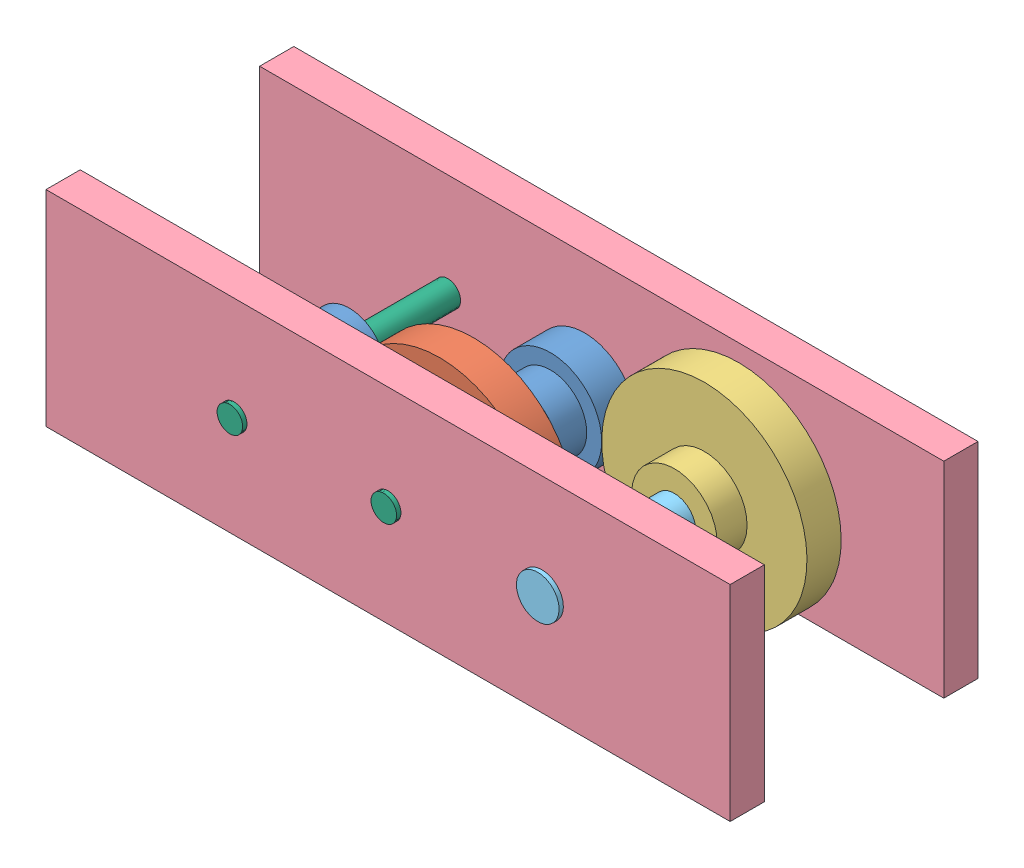
SolidWorks assembly Assem2, configuration Default. Lengths in mm.
Overall size (508 199.15 190.5).
9 component instances, 6 part files, 18 mates.
Components (placement in the parent):
- gear1-1: gear1 [Default] at (-46.2625 76.2 262.9741) x (-1 0 0) z (0 0 -1) size (76.2 76.2 47.5)
- gear2-1: gear2 [Default] at (68.0375 76.2 237.5741) x (0.923728 -0.383049 0) z (0 0 1) size (152.4 152.4 47.62)
- gear1-2: gear1 [Default] at (68.0375 76.2 155.1511) x (0.923728 -0.383049 0) z (0 0 1) size (76.2 76.2 47.5)
- gear3-1: gear3 [Default] at (182.3375 76.2 155.1511) x (0.923728 -0.383049 0) z (0 0 1) size (152.4 152.4 47.62)
- side-1: side [Default] at (68.0375 76.2 301.0741) x (1 0 0) z (0 0 -1) size (508 152.4 25.4)
- rod2-1: rod2 [Default] at (182.3375 76.2 304.2491) x (0.923728 -0.383049 0) z (0.383049 0.923728 0) size (31.75 190.5 31.75)
- side-2: side [Default] at (68.0375 76.2 117.0511) size (508 152.4 25.4)
- rod1-1: rod1 [Default] at (68.0375 76.2 113.7491) x (0 0 1) z (-0.923728 0.383049 0) size (190.5 19.05 19.05)
- rod1-2: rod1 [Default] at (-46.2625 76.2 113.7491) x (0 0 1) z (-0.923728 0.383049 0) size (190.5 19.05 19.05)
Mates (geometry in assembly coordinates):
- Distance1: distance = 12.7 mm anti-aligned: plane of gear2-1 through (68.0375 76.2 262.9741) normal (0 0 1); plane of side-1 through (68.0375 76.2 275.6741) normal (0 0 -1)
- Concentric3: concentric aligned: cylinder of gear2-1 through (36.132 5.8682 215.3491) axis (0 0 1) radius 31.75; cylinder of side-1 through (36.132 5.8682 275.6741) axis (0 0 1) radius 9.525
- Concentric4: concentric aligned: cylinder of gear1-1 through (-69.4501 -37.9143 237.5741) axis (0 0 1) radius 38.1; cylinder of side-1 through (-69.4501 -37.9143 275.6741) axis (0 0 1) radius 9.525
- Coincident2: coincident aligned: plane of gear1-1 through (-69.4501 -37.9143 262.9741) normal (0 0 1); plane of gear2-1 through (36.132 5.8682 262.9741) normal (0 0 1)
- Concentric6: concentric anti-aligned: cylinder of gear2-1 through (36.132 5.8682 215.3491) axis (0 0 1) radius 31.75; cylinder of gear1-2 through (36.132 5.8682 202.6491) axis (0 0 -1) radius 26.9875
- Distance3: distance = 12.7 mm anti-aligned: plane of gear2-1 through (68.0375 76.2 215.3491) normal (0 0 -1); plane of gear1-2 through (68.0375 76.2 202.6491) normal (0 0 1)
- Concentric7: concentric anti-aligned: cylinder of gear3-1 through (141.7141 49.6507 202.7761) axis (0 0 -1) radius 31.75; cylinder of side-1 through (141.7141 49.6507 275.6741) axis (0 0 1) radius 15.875
- Coincident5: coincident aligned: plane of gear1-2 through (36.132 5.8682 155.1511) normal (0 0 -1); plane of gear3-1 through (141.7141 49.6507 155.1511) normal (0 0 -1)
- Coincident6: coincident aligned: plane of side-1 through (-227.6832 -21.0382 275.6741) normal (-0.383049 0.923728 0); plane of side-2 through (-227.6832 -21.0382 142.4511) normal (-0.383049 0.923728 0)
- Coincident7: coincident aligned: plane of side-1 through (241.5706 173.5507 275.6741) normal (0.923728 0.383049 0); plane of side-2 through (299.9473 32.7745 142.4511) normal (0.923728 0.383049 0)
- Distance4: distance = 12.7 mm anti-aligned: plane of gear3-1 through (182.3375 76.2 155.1511) normal (0 0 -1); plane of side-2 through (68.0375 76.2 142.4511) normal (0 0 1)
- Concentric8: concentric anti-aligned: cylinder of rod2-1 through (141.7141 49.6507 113.7491) axis (0 0 1) radius 15.875; cylinder of side-2 through (141.7141 49.6507 142.4511) axis (0 0 -1) radius 15.875
- Distance5: distance = 3.175 mm aligned: plane of rod2-1 through (182.3375 76.2 304.2491) normal (0 0 1); plane of side-1 through (68.0375 76.2 301.0741) normal (0 0 1)
- Concentric9: concentric anti-aligned: cylinder of side-1 through (36.132 5.8682 275.6741) axis (0 0 1) radius 9.525; cylinder of rod1-1 through (36.132 5.8682 304.2491) axis (0 0 -1) radius 9.525
- Distance6: distance = 3.175 mm aligned: plane of rod1-1 through (68.0375 76.2 304.2491) normal (0 0 1); plane of side-1 through (68.0375 76.2 301.0741) normal (0 0 1)
- Concentric10: concentric anti-aligned: cylinder of side-1 through (-69.4501 -37.9143 275.6741) axis (0 0 1) radius 9.525; cylinder of rod1-2 through (-69.4501 -37.9143 304.2491) axis (0 0 -1) radius 9.525
- Distance7: distance = 3.175 mm aligned: plane of rod1-2 through (-46.2625 76.2 304.2491) normal (0 0 1); plane of side-1 through (68.0375 76.2 301.0741) normal (0 0 1)
- Coincident13: coincident anti-aligned: plane of side-2 through (-185.9625 0 142.4511) normal (0 -1 0); plane of assembly
